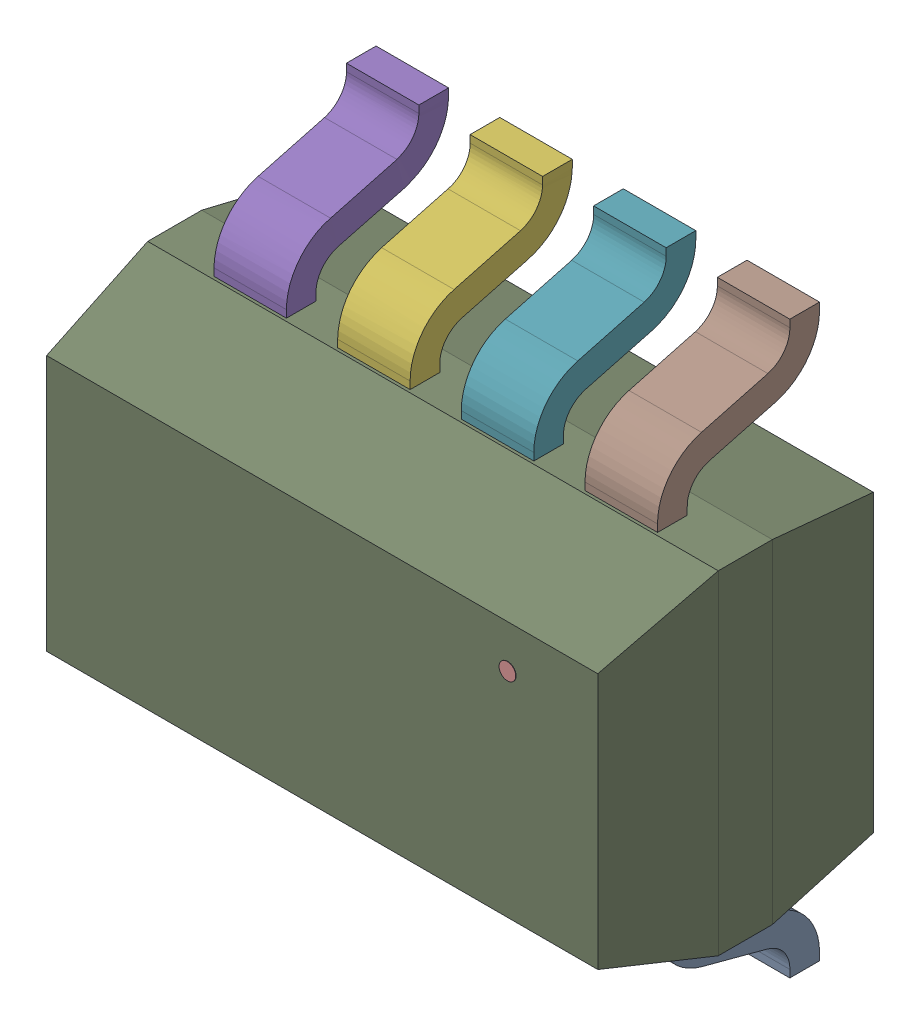
SolidWorks assembly U8, configuration Standard. Lengths in mm.
Overall size (3 3.01 1.46).
11 component instances, 10 part files, 0 mates.
Components (placement in the parent):
- U8-subassembly-1-1: U8-subassembly-1 [Standard] at (-13.7 -7.3 0) x (0 -1 0) z (0 0 1) size (3.01 3 1.46)
  - 21-0078H_MXM-M-1: 21-0078H_MXM-M [Standard] at origin size (0.62 0.39 0.85)
  - 21-0078H_MXM-M-1-1: 21-0078H_MXM-M-1 [Standard] at origin size (0.63 0.39 0.86)
  - 21-0078H_MXM-M-2-1: 21-0078H_MXM-M-2 [Standard] at origin size (0.62 0.39 0.85)
  - 21-0078H_MXM-M-3-1: 21-0078H_MXM-M-3 [Standard] at origin size (0.62 0.39 0.85)
  - 21-0078H_MXM-M-4-1: 21-0078H_MXM-M-4 [Standard] at origin size (0.63 0.39 0.86)
  - 21-0078H_MXM-M-5-1: 21-0078H_MXM-M-5 [Standard] at origin size (0.63 0.39 0.86)
  - 21-0078H_MXM-M-6-1: 21-0078H_MXM-M-6 [Standard] at origin size (0.62 0.39 0.85)
  - 21-0078H_MXM-M-7-1: 21-0078H_MXM-M-7 [Standard] at origin size (0.62 0.39 0.85)
  - 21-0078H_MXM-M-8-1: 21-0078H_MXM-M-8 [Standard] at origin size (1.76 3 1.45)
  - 21-0078H_MXM-M-9-1: 21-0078H_MXM-M-9 [Standard] at origin size (0.09 0.09 0)
